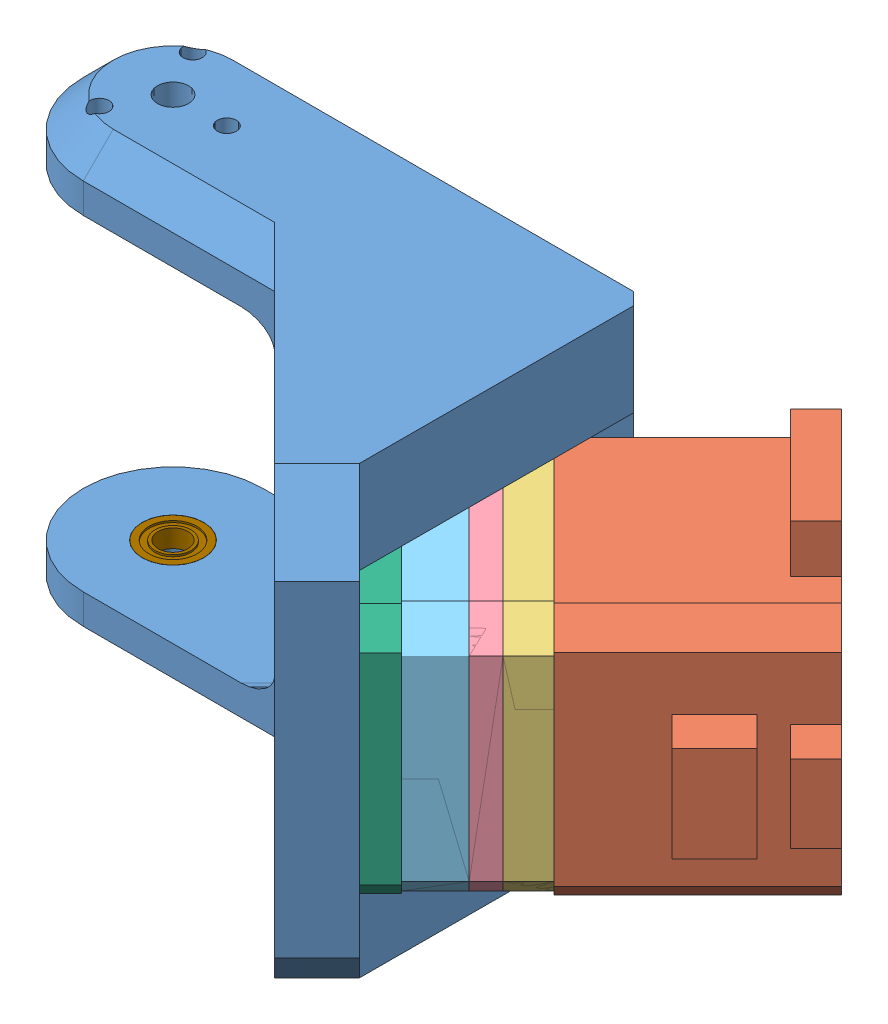
SolidWorks assembly 关节2, configuration 默认. Lengths in mm.
Overall size (136.31 74.6 78.71).
10 component instances, 9 part files, 8 mates.
Components (placement in the parent):
- 关节2-底座-1: 关节2-底座 [默认] at (-22.4957 5.6427 65) size (91.05 74.6 66.98)
- 42步进电机+减速器-1: 42步进电机+减速器 [默认] at (93.8622 -42.7573 69.6055) x (0 1 0) z (0.707107 0 0.707107) size (50.3 57 49.3)
  - 42步进电机-1: 42步进电机 [默认] at origin size (50.3 56.5 49.3)
  - 主壳 v1-11-1: 主壳 v1-11 [默认] at (0.15 34 -0.15) x (1 0 0) z (0 1 0) size (42 42 8)
  - 主壳 v1-2-1: 主壳 v1-2 [默认] at (0.15 40 -0.15) x (1 0 0) z (0 1 0) size (42 42 4)
  - 谐波减速器-1: 谐波减速器 [默认] at (42.15 52 -0.15) x (-1 0 0) z (0 -1 0) size (42 42 10)
  - 外壳-上部-1: 外壳-上部 [默认] at (0.15 57 -0.15) x (0 0 -1) z (-1 0 0) size (42 5 42)
  - 输出2-1: 输出2 [默认] at (21.15 52 -21.15) x (0.999253 0 -0.03864) z (0.03864 0 0.999253) size (28 5 28)
- 轴承25x37x7-1: 轴承25x37x7 [默认] at (36.1269 -21.6073 97.4302) x (0.5 0.707107 0.5) z (0.5 -0.707107 0.5) size (37 7 37)
- 挡边轴承5x9x3-1: 挡边轴承5x9x3 [默认] at (-22.4957 -50.3573 65) x (0.981078 0 0.193612) z (-0.193612 0 0.981078) size (10.2 3 10.2)
Mates (geometry in assembly coordinates):
- 同心1: concentric anti-aligned: cylinder of 关节2-底座-1 through (33.652 -21.6073 99.9051) axis (0.707107 0 -0.707107) radius 18.6; cylinder of 轴承25x37x7-1 through (38.6018 -21.6073 94.9553) axis (-0.707107 0 0.707107) radius 18.5
- 重合4: coincident anti-aligned: plane of 关节2-底座-1 through (33.652 -21.6073 99.9051) normal (0.707107 0 -0.707107); plane of 轴承25x37x7-1 through (33.652 -21.6073 99.9051) normal (-0.707107 0 0.707107)
- 重合5: coincident anti-aligned: plane of 关节2-底座-1 through (53.5571 -111.1573 109.9106) normal (0.707107 0 -0.707107); plane of 42步进电机+减速器-1/输出-2-1 through (31.6135 -20.6085 87.967) normal (-0.707107 0 0.707107)
- 同心2: concentric aligned: cylinder of 关节2-底座-1 through (28.7023 -21.6073 104.8548) axis (0.707107 0 -0.707107) radius 13; cylinder of 42步进电机+减速器-1/42步进电机-1 through (38.9553 -21.6073 94.6018) axis (0.707107 0 -0.707107) radius 2.5
- 同心3: concentric aligned: cylinder of 关节2-底座-1 through (-22.4957 -51.8573 65) axis (0 1 0) radius 4.6; cylinder of 挡边轴承5x9x3-1 through (-22.4957 -51.8573 65) axis (0 1 0) radius 4.5
- 重合6: coincident anti-aligned: plane of 关节2-底座-1 through (-22.4957 -49.4573 65) normal (0 1 0); plane of 挡边轴承5x9x3-1 through (-22.4957 -49.4573 65) normal (0 -1 0)
- 同心4: concentric anti-aligned: cylinder of 关节2-底座-1 through (39.2909 -6.1073 116.1865) axis (0.707107 0 -0.707107) radius 1.6; cylinder of 42步进电机+减速器-1/外壳-上部-1 through (51.8954 -6.1073 103.582) axis (-0.707107 0 0.707107) radius 3
- 重合7: coincident anti-aligned: plane of 关节2-底座-1 through (53.5571 -111.1573 109.9106) normal (0.707107 0 -0.707107); plane of 42步进电机+减速器-1/外壳-上部-1 through (53.451 -42.6073 109.8046) normal (-0.707107 0 0.707107)
